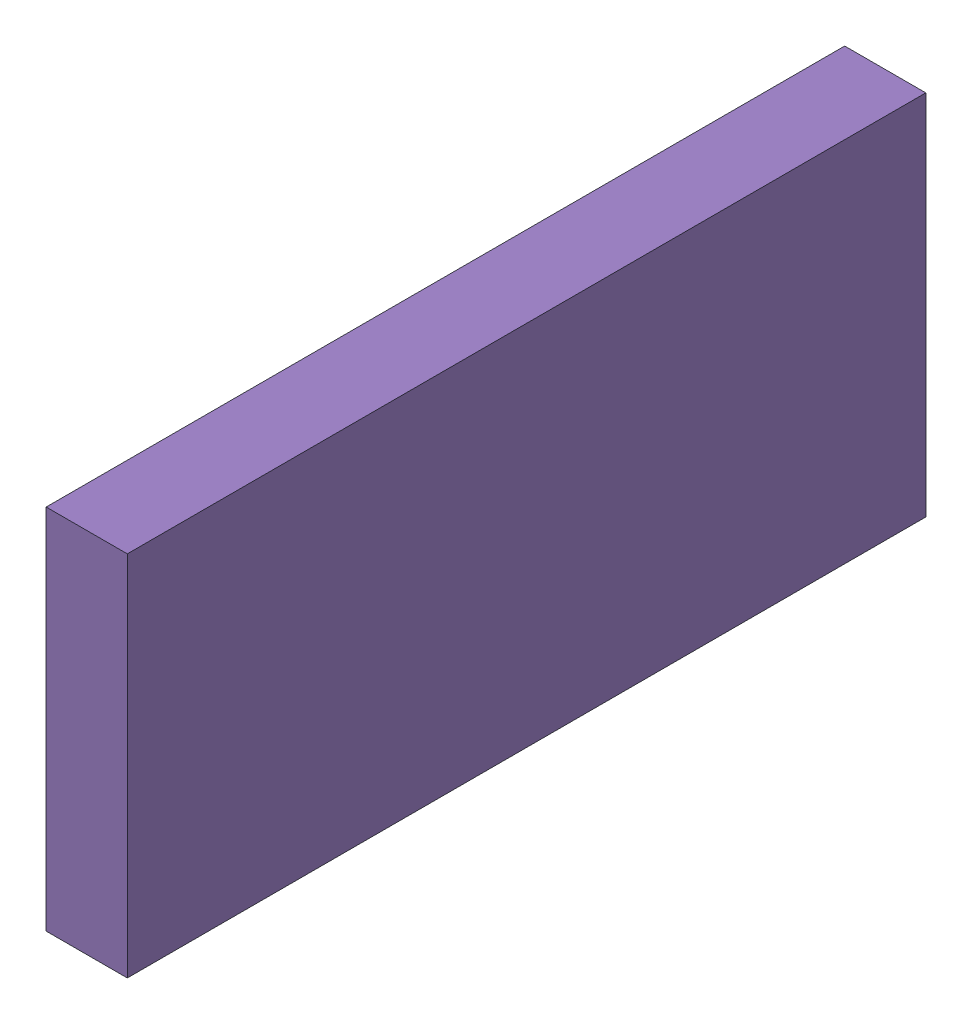
SolidWorks assembly C8, configuration Default. Lengths in mm.
Overall size (0.25 1.15 2.5).
24 component instances, 7 part files, 0 mates.
Components (placement in the parent):
- 6701982208-1: 6701982208 [Default] at (27.7 14.8 0) (suppressed, hidden)
- 6327399040-1: 6327399040 [Default] at (4.2287 12.3 -2.0431) x (0 0 -1) z (1 0 0) size (0.4 0.85 0.25)
  - 6701982208-1: 6701982208 [Default] at (27.7 14.8 0) (suppressed, hidden)
  - Extruded-7-1: Extruded-7 [Default] at origin size (0.4 0.85 0.25)
- 6327399232-1: 6327399232 [Default] at (4.2287 12.3 -2.0431) x (0 0 -1) z (1 0 0) size (1.75 0.95 0.25)
  - 6701982208-1: 6701982208 [Default] at (27.7 14.8 0) (suppressed, hidden)
  - Extruded-8-1: Extruded-8 [Default] at origin size (1.75 0.95 0.25)
- 6327399424-1: 6327399424 [Default] at (4.2287 12.3 -2.0431) x (0 0 -1) z (1 0 0) size (1.85 1.05 0.25)
  - 6701982208-1: 6701982208 [Default] at (27.7 14.8 0) (suppressed, hidden)
  - Extruded-9-1: Extruded-9 [Default] at origin size (1.85 1.05 0.25)
- 6327399616-1: 6327399616 [Default] at (4.2287 12.3 -2.0431) x (0 0 -1) z (1 0 0) size (2.4 1.05 0.25)
  - 6701982208-1: 6701982208 [Default] at (27.7 14.8 0) (suppressed, hidden)
  - Extruded-10-1: Extruded-10 [Default] at origin size (2.4 1.05 0.25)
- 6327399808-1: 6327399808 [Default] at (4.2287 12.3 -2.0431) x (0 0 -1) z (1 0 0) size (2.5 1.15 0.25)
  - 6701982208-1: 6701982208 [Default] at (27.7 14.8 0) (suppressed, hidden)
  - Extruded-11-1: Extruded-11 [Default] at origin size (2.5 1.15 0.25)
- 6327400000-1: 6327400000 [Default] at (4.2287 12.3 -2.0431) x (0 0 -1) z (1 0 0) size (2.4 1.05 0.25)
  - 6701982208-1: 6701982208 [Default] at (27.7 14.8 0) (suppressed, hidden)
  - Extruded-12-1: Extruded-12 [Default] at origin size (2.4 1.05 0.25)
- 6327397696-1: 6327397696 [Default] at (3.5327 12.3 -2.0431) x (0 0 -1) z (1 0 0)
  - 6701982208-1: 6701982208 [Default] at (27.7 14.8 0) (suppressed, hidden)
- 6327400960-1: 6327400960 [Default] at (4.2287 12.3 -2.0431) x (0 0 -1) z (1 0 0) size (0.95 0.95 0.25)
  - 6701982208-1: 6701982208 [Default] at (27.7 14.8 0) (suppressed, hidden)
  - Extruded-14-1: Extruded-14 [Default] at origin size (0.95 0.95 0.25)
